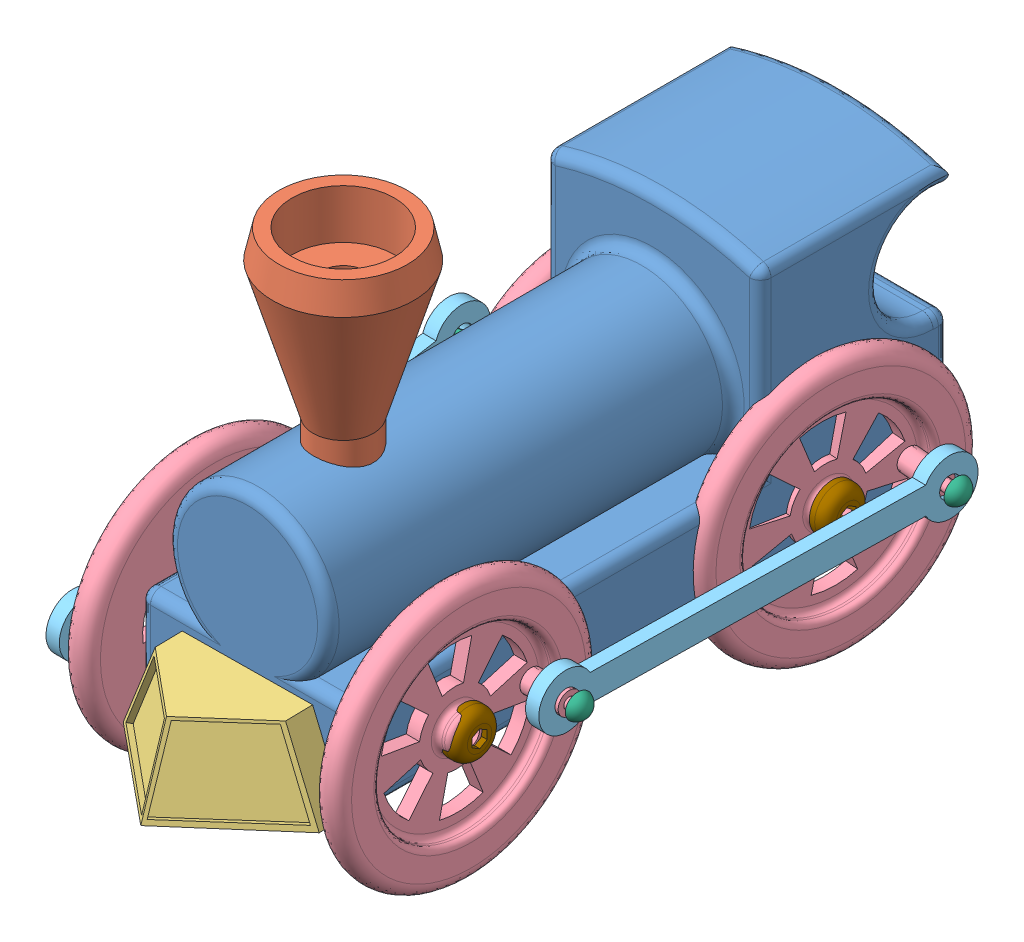
SolidWorks assembly TrainASsembly, configuration Default. Lengths in mm.
Overall size (90.09 129.27 182.19).
19 component instances, 9 part files, 4 mates.
Components (placement in the parent):
- Train Body-1: Train Body [Default] at (64.7823 45.3857 165.669) size (51.15 67.68 139.75)
- Smokestack-1: Smokestack [Default] at (84.3772 88.5039 143.2689) size (33.14 44.87 33.14)
- Cow Catcher-1: Cow Catcher [Default] at (64.7013 35.7425 185.6804) x (-0.999947 -0.000166 0.010248) z (-0.010249 0.008725 -0.999909) size (45.64 19.05 28.11)
- Wheel-1: Wheel [Default] at (102.5584 45.4193 172.7517) x (0.999848 0.003777 0.017039) z (-0.016776 -0.06108 0.997992) size (15.61 60.58 60.58)
- Wheel-2: Wheel [Default] at (98.7836 45.3479 82.7855) x (0.996258 0.000577 0.086427) z (-0.086231 -0.061047 0.994403) size (15.61 60.58 60.58)
- Wheel-3: Wheel [Default] at (51.3107 55.3331 120.7935) x (-0.999848 -0.008988 -0.014959) z (0.011424 0.310837 -0.950395) size (15.61 60.58 60.58)
- Wheel-4: Wheel [Default] at (54.2394 30.5997 38.61) x (-0.999848 -0.008988 -0.014959) z (0.017385 -0.587704 -0.808889) size (15.61 60.58 60.58)
- Wheel Arm-1: Wheel Arm [Default] at (34.4121 37.5881 103.7569) x (0.013042 0.184706 -0.982707) z (0.999848 0.008988 0.014959) size (101.64 12.92 3.17)
- Wheel Arm-2: Wheel Arm [Default] at (112.7233 33.5921 70.8329) x (0.017039 -0.000001 -0.999855) z (0.999848 0.003777 0.017039) size (101.64 12.92 3.17)
- Wheel Peg-1: Wheel Peg [Default] at (105.5011 48.3526 38.565) x (0.000574 -1 0.000051) z (-0.086427 0.000001 0.996258) size (5.87 15.02 5.87)
- Wheel Peg-2: Wheel Peg [Default] at (104.6935 48.2739 126.8578) x (0.000574 -1 0.000051) z (-0.086427 0.000001 0.996258) size (5.87 15.02 5.87)
- Wheel Peg-3: Wheel Peg [Default] at (46.7076 59.54 74.9915) x (-0.139742 0.990188 0.000051) z (0.085586 0.012027 0.996258) size (5.87 15.02 5.87)
- Back Peg-1: Back Peg [Default] at (79.2544 45.7889 26.1927) x (1 0 0) z (0 0.998135 -0.061049) size (8.83 16.46 8.83)
- Wheel Peg-4: Wheel Peg [Default] at (46.1097 43.1656 162.0249) x (-0.139742 0.990188 0.000051) z (0.085586 0.012027 0.996258) size (5.87 15.02 5.87)
- Hitch Magnet-1: Hitch Magnet [Default] at (78.5273 45.6401 12.3117) x (1 0 0) z (0 -0.999962 0.008727) size (11.36 6.35 11.36)
- Screw-1: Screw [Default] at (49.5639 45.4603 60.596) x (-0.008727 0 0.999962) z (-0.999962 0 -0.008727) size (10.71 10.71 20.07)
- Screw-2: Screw [Default] at (45.9551 47.7275 146.4021) x (-0.008727 0 0.999962) z (-0.999962 0 -0.008727) size (10.71 10.71 20.07)
- Screw-3: Screw [Default] at (106.834 46.4281 144.4944) x (0.01745 0.000305 -0.999848) z (0.999695 0.01745 0.017452) size (10.71 10.71 20.07)
- Screw-4: Screw [Default] at (104.753 46.4281 55.6416) x (0.01745 0.000305 -0.999848) z (0.999695 0.01745 0.017452) size (10.71 10.71 20.07)
Mates (geometry in assembly coordinates):
- Concentric1: concentric anti-aligned: circle of chooChooWheel-3; circle of arm-1
- Coincident6: coincident anti-aligned: plane of chooChooWheel-4 through (37.8537 56.6989 74.4913) normal (-0.999848 -0.008988 -0.014959); circle of arm-1
- Concentric2: concentric aligned: circle of chooChooWheel-1; circle of arm-2
- Coincident7: coincident anti-aligned: plane of chooChooWheel-2 through (118.1871 48.0825 39.7371) normal (0.996258 0.000577 0.086427); circle of differentPeg-1
